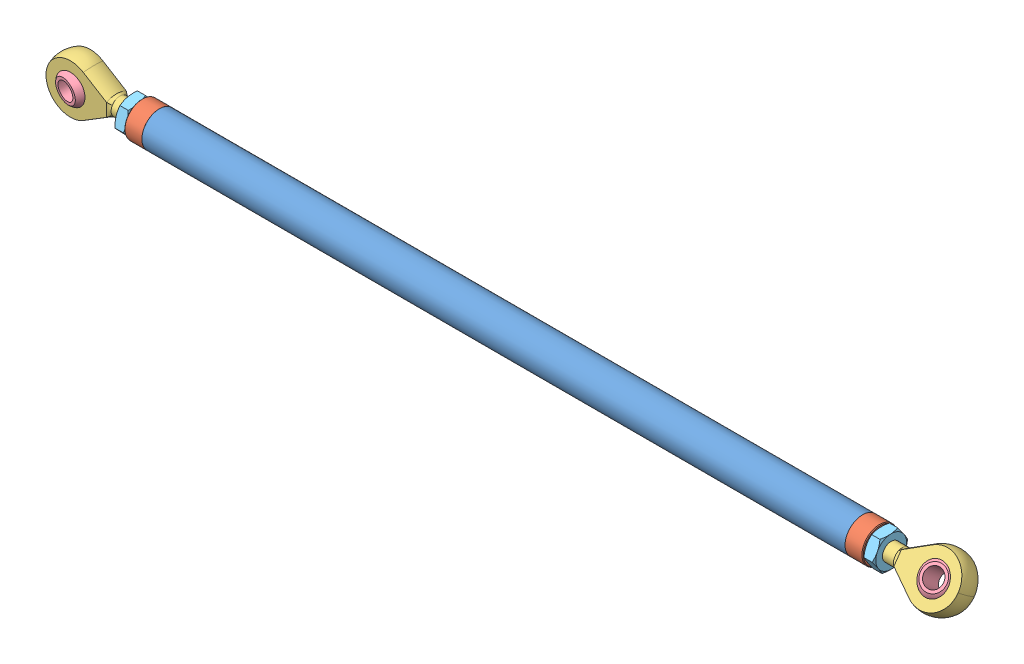
SolidWorks assembly SP-10011-BA-Push Rod Front, configuration Default. Lengths in mm.
Overall size (330.69 22.98 21.3).
11 component instances, 5 part files, 14 mates.
Components (placement in the parent):
- Part4^SP-10011-BA-Push Rod Front-1: Part4^SP-10011-BA-Push Rod Front [Default] at origin size (254 12.7 12.7) (virtual)
- SP-10003-AC-Threaded Insert-1: SP-10003-AC-Threaded Insert [AM-4 Rod End Thread] at (-117.475 0 0) x (0 0.430975 0.902364) z (-1 0 0) size (12.7 12.7 15.88)
- SP-10003-AC-Threaded Insert-2: SP-10003-AC-Threaded Insert [AM-4 Rod End Thread] at (117.475 0 0) x (0 0 -1) z (1 0 0) size (12.7 12.7 15.88)
- FS-MALE ROD END UNF-3A, 0.25x28-0.25D (AM-4)-1: FS-MALE ROD END UNF-3A, 0.25x28-0.25D (AM-4) [Default] at (-155.575 0 0) x (0 -1 0) z (1 0 0) size (19.32 12.47 49.44)
  - Body^FS-MALE ROD END UNF-3A, 0.25x28-0.25D (AM-4)-2: Body^FS-MALE ROD END UNF-3A, 0.25x28-0.25D (AM-4) [Default] at origin size (19.32 7.2 49.44) (virtual)
  - Ball^FS-MALE ROD END UNF-3A, 0.25x28-0.25D (AM-4)-2: Ball^FS-MALE ROD END UNF-3A, 0.25x28-0.25D (AM-4) [Default] x (0.086179 -0.13783 0.9867) z (-0.991806 -0.105624 0.071871) size (12.7 9.53 12.7) (virtual)
- FS-MALE ROD END UNF-3A, 0.25x28-0.25D (AM-4)-2: FS-MALE ROD END UNF-3A, 0.25x28-0.25D (AM-4) [Default] at (155.575 0 0) x (0 0.819152 -0.573576) z (-1 0 0) size (19.32 12.47 49.44)
  - Body^FS-MALE ROD END UNF-3A, 0.25x28-0.25D (AM-4)-2: Body^FS-MALE ROD END UNF-3A, 0.25x28-0.25D (AM-4) [Default] at origin size (19.32 7.2 49.44) (virtual)
  - Ball^FS-MALE ROD END UNF-3A, 0.25x28-0.25D (AM-4)-2: Ball^FS-MALE ROD END UNF-3A, 0.25x28-0.25D (AM-4) [Default] x (0.086179 -0.13783 0.9867) z (-0.991806 -0.105624 0.071871) size (12.7 9.53 12.7) (virtual)
- FS-ZINC YELLOW THIN NUT G8 HX, 0.25x28-0.15625 (93839A805)-1: FS-ZINC YELLOW THIN NUT G8 HX, 0.25x28-0.15625 (93839A805) [Default] at (135.3344 0 0) x (0 -0.997757 -0.066945) z (0 -0.066945 0.997757) size (11.11 3.97 12.83)
- FS-ZINC YELLOW THIN NUT G8 HX, 0.25x28-0.15625 (93839A805)-2: FS-ZINC YELLOW THIN NUT G8 HX, 0.25x28-0.15625 (93839A805) [Default] at (-135.3344 0 0) x (0 0.971407 0.237421) z (0 -0.237421 0.971407) size (11.11 3.97 12.83)
Mates (geometry in assembly coordinates):
- Concentric1: concentric aligned: cylinder of Part4^Assem1-1 through (-127.001 0 0) axis (1 0 0) radius 4.7625; cylinder of SP-10003-AC-Threaded Insert-1 through (-127 0 0) axis (1 0 0) radius 4.8768
- Coincident1: coincident anti-aligned: plane of Part4^Assem1-1 through (-127 0 0) normal (-1 0 0); plane of SP-10003-AC-Threaded Insert-1 through (-127 0 0) normal (1 0 0)
- Concentric2: concentric anti-aligned: cylinder of Part4^Assem1-1 through (-127.001 0 0) axis (1 0 0) radius 4.7625; cylinder of SP-10003-AC-Threaded Insert-2 through (127 0 0) axis (-1 0 0) radius 4.8768
- Coincident2: coincident anti-aligned: plane of Part4^Assem1-1 through (127 0 0) normal (1 0 0); plane of SP-10003-AC-Threaded Insert-2 through (127 0 0) normal (-1 0 0)
- Concentric3: concentric aligned: cylinder of SP-10003-AC-Threaded Insert-1 through (-133.35 0 0) axis (-1 0 0) radius 2.7051; cylinder of FS-MALE ROD END UNF-3A, 0.25x28-0.25D (AM-4)-1/Body^FS-MALE ROD END UNF-3A, 0.25x28-0.25D (AM-4)-2 through (-115.9002 0 0) axis (-1 0 0) radius 3.175
- Concentric4: concentric: cylinder of FS-MALE ROD END UNF-3A, 0.25x28-0.25D (AM-4)-1/Ball^FS-MALE ROD END UNF-3A, 0.25x28-0.25D (AM-4)-2 through (-157.4267 -1.1978 12.5071) axis (-0.145804 -0.094313 0.984808) radius 3.175
- Concentric5: concentric aligned: cylinder of SP-10003-AC-Threaded Insert-2 through (133.35 0 0) axis (1 0 0) radius 2.7051; cylinder of FS-MALE ROD END UNF-3A, 0.25x28-0.25D (AM-4)-2/Body^FS-MALE ROD END UNF-3A, 0.25x28-0.25D (AM-4)-2 through (115.9002 0 0) axis (1 0 0) radius 3.175
- Concentric6: concentric: cylinder of FS-MALE ROD END UNF-3A, 0.25x28-0.25D (AM-4)-2/Ball^FS-MALE ROD END UNF-3A, 0.25x28-0.25D (AM-4)-2 through (157.4267 8.1549 9.5582) axis (0.145804 0.642119 0.752611) radius 3.175
- Angle1: planar angle = 0.610865 rad aligned: plane of FS-MALE ROD END UNF-3A, 0.25x28-0.25D (AM-4)-2/Body^FS-MALE ROD END UNF-3A, 0.25x28-0.25D (AM-4)-2 through (155.575 2.0469 2.9233) normal (0 0.573576 0.819152)
- Parallel2: parallel aligned: plane of FS-MALE ROD END UNF-3A, 0.25x28-0.25D (AM-4)-1/Body^FS-MALE ROD END UNF-3A, 0.25x28-0.25D (AM-4)-2 through (-155.575 0 3.5687) normal (0 0 1)
- Concentric7: concentric anti-aligned: cylinder of FS-MALE ROD END UNF-3A, 0.25x28-0.25D (AM-4)-2/Body^FS-MALE ROD END UNF-3A, 0.25x28-0.25D (AM-4)-2 through (115.9002 0 0) axis (1 0 0) radius 3.175; cylinder of FS-ZINC YELLOW THIN NUT G8 HX, 0.25x28-0.15625 (93839A805)-1 through (137.3187 0 0) axis (-1 0 0) radius 3.175
- Coincident7: coincident anti-aligned: plane of SP-10003-AC-Threaded Insert-2 through (133.35 0 0) normal (1 0 0); plane of FS-ZINC YELLOW THIN NUT G8 HX, 0.25x28-0.15625 (93839A805)-1 through (133.35 5.7585 -2.8287) normal (-1 0 0)
- Concentric8: concentric anti-aligned: cylinder of FS-MALE ROD END UNF-3A, 0.25x28-0.25D (AM-4)-1/Body^FS-MALE ROD END UNF-3A, 0.25x28-0.25D (AM-4)-2 through (-115.9002 0 0) axis (-1 0 0) radius 3.175; cylinder of FS-ZINC YELLOW THIN NUT G8 HX, 0.25x28-0.15625 (93839A805)-2 through (-137.3187 0 0) axis (1 0 0) radius 3.175
- Coincident8: coincident anti-aligned: plane of SP-10003-AC-Threaded Insert-1 through (-133.35 0 0) normal (-1 0 0); plane of FS-ZINC YELLOW THIN NUT G8 HX, 0.25x28-0.15625 (93839A805)-2 through (-133.35 -4.6358 -4.4353) normal (1 0 0)
